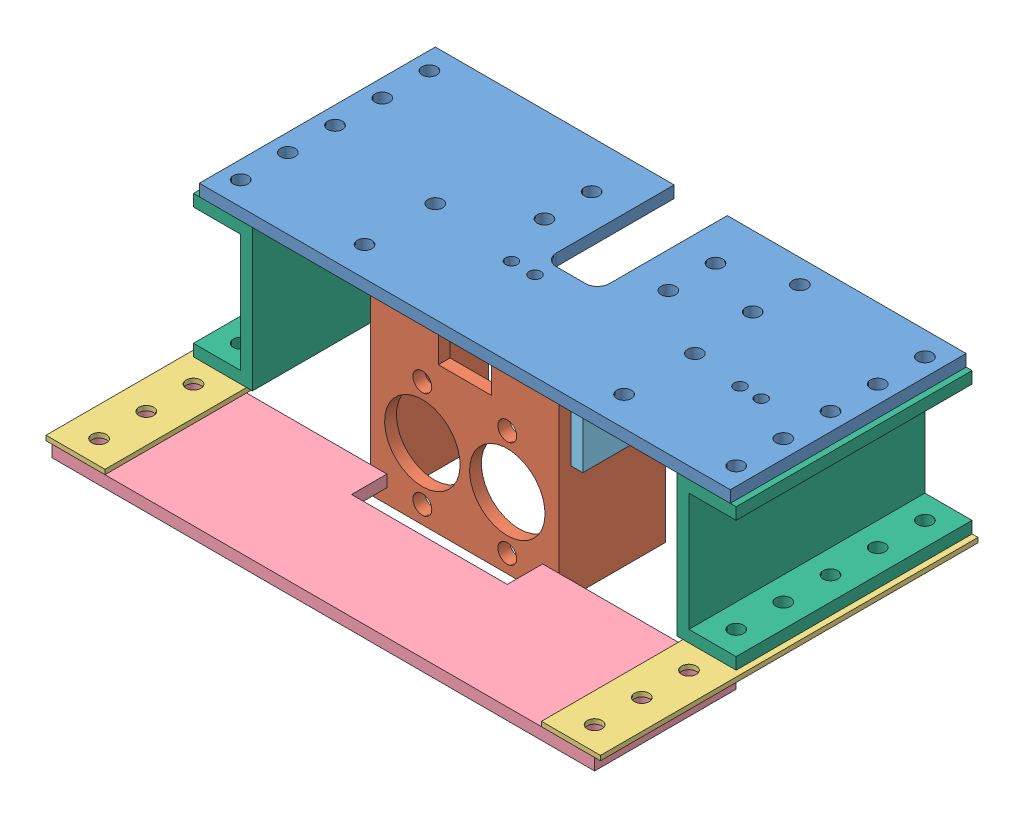
SolidWorks assembly Static Structure, configuration Default. Lengths in mm.
Overall size (298.45 99.21 203.2).
8 component instances, 6 part files, 23 mates.
Components (placement in the parent):
- Base Plate-1: Base Plate [Default] at (-589.1939 -24.2998 134.4277) x (-1 0 0) z (0 0 -1) size (285.75 6.35 127)
- C Bracket-1: C Bracket [Default] at (118.646 23.994 204.1743) x (1 0 0) z (0 -1 0) size (101.6 57.15 92.86)
- Chassis Tabs-1: Chassis Tabs [Default] at (40.6574 -52.206 309.9275) size (298.45 2.54 203.2)
- Foot Rest-1: Foot Rest [Default] at (-89.2227 -61.096 337.6277) size (292.1 6.35 76.2)
- L Bracket-1: L Bracket [Default] at (6.0273 23.994 255.0777) x (0 0 -1) z (-1 0 0) size (57.15 31.75 31.75)
- L Bracket-2: L Bracket [Default] at (107.6273 23.994 197.9277) x (0 0 1) z (1 0 0) size (57.15 31.75 31.75)
- Risers-1: Risers [Default] at (-86.4131 -13.4586 261.4277) x (0 0 -1) z (-1 0 0) size (127 76.2 31.75)
- Risers-2: Risers [Default] at (200.0678 -13.4586 134.4277) x (0 0 1) z (1 0 0) size (127 76.2 31.75)
Mates (geometry in assembly coordinates):
- Coincident1: coincident anti-aligned: plane of Base Plate-1 through (-589.1939 23.994 261.4277) normal (0 -1 0); plane of Risers-1 through (-86.4131 23.994 134.4277) normal (0 1 0)
- Coincident2: coincident anti-aligned: plane of Base Plate-1 through (-589.1939 23.994 261.4277) normal (0 -1 0); plane of Risers-2 through (200.0678 23.994 261.4277) normal (0 1 0)
- Coincident5: coincident anti-aligned: plane of Foot Rest-1 through (-89.2227 -54.746 337.6277) normal (0 1 0); plane of Chassis Tabs-1 through (40.6574 -54.746 309.9275) normal (0 -1 0)
- Coincident7: coincident aligned: plane of Chassis Tabs-1 through (-92.3977 -54.746 337.6277) normal (0 0 1); plane of Foot Rest-1 through (-89.2227 -54.746 337.6277) normal (0 0 1)
- Coincident8: coincident anti-aligned: plane of Chassis Tabs-1 through (40.6574 -52.206 309.9275) normal (0 1 0); plane of Risers-1 through (-86.4131 -52.206 134.4277) normal (0 -1 0)
- Coincident11: coincident anti-aligned: plane of C Bracket-1 through (6.0273 -68.8709 204.1743) normal (-1 0 0); plane of L Bracket-1 through (6.0273 23.994 197.9277) normal (1 0 0)
- Concentric9: concentric aligned: cylinder of C Bracket-1 through (107.6273 4.944 216.9777) axis (-1 0 0) radius 3.9688; cylinder of L Bracket-1 through (6.0283 4.944 216.9777) axis (-1 0 0) radius 3.9688
- Concentric10: concentric aligned: cylinder of C Bracket-1 through (107.6273 4.944 236.0277) axis (-1 0 0) radius 3.9688; cylinder of L Bracket-1 through (6.0283 4.944 236.0277) axis (-1 0 0) radius 3.9688
- Concentric11: concentric anti-aligned: cylinder of C Bracket-1 through (107.6273 4.944 236.0277) axis (-1 0 0) radius 3.9688; cylinder of L Bracket-2 through (107.6263 4.944 236.0277) axis (1 0 0) radius 3.9688
- Concentric12: concentric anti-aligned: cylinder of C Bracket-1 through (107.6273 4.944 216.9777) axis (-1 0 0) radius 3.9688; cylinder of L Bracket-2 through (107.6263 4.944 216.9777) axis (1 0 0) radius 3.9688
- Coincident13: coincident anti-aligned: plane of C Bracket-1 through (107.6273 -68.8709 204.1743) normal (1 0 0); plane of L Bracket-2 through (107.6273 23.994 255.0777) normal (-1 0 0)
- Coincident14: coincident anti-aligned: plane of Base Plate-1 through (-589.1939 23.994 261.4277) normal (0 -1 0); plane of L Bracket-1 through (6.0273 23.994 197.9277) normal (0 1 0)
- Concentric14: concentric anti-aligned: cylinder of Base Plate-1 through (190.1773 23.993 147.1277) axis (0 1 0) radius 3.9688; cylinder of Risers-2 through (190.1773 23.994 147.1277) axis (0 -1 0) radius 3.9688
- Concentric15: concentric anti-aligned: cylinder of Base Plate-1 through (190.1773 23.993 248.7277) axis (0 1 0) radius 3.9688; cylinder of Risers-2 through (190.1773 23.994 248.7277) axis (0 -1 0) radius 3.9688
- Concentric16: concentric anti-aligned: cylinder of Base Plate-1 through (-76.5227 23.993 147.1277) axis (0 1 0) radius 3.9688; cylinder of Risers-1 through (-76.5227 23.994 147.1277) axis (0 -1 0) radius 3.9688
- Concentric17: concentric anti-aligned: cylinder of Base Plate-1 through (-76.5227 23.993 248.7277) axis (0 1 0) radius 3.9688; cylinder of Risers-1 through (-76.5227 23.994 248.7277) axis (0 -1 0) radius 3.9688
- Coincident15: coincident aligned: plane of Chassis Tabs-1 through (-92.3977 -54.746 134.4277) normal (0 0 -1); plane of Risers-1 through (-86.4131 -13.4586 134.4277) normal (0 0 -1)
- Distance1: distance = 3.175 mm aligned: plane of Chassis Tabs-1 through (-92.3977 -54.746 134.4277) normal (-1 0 0); plane of Risers-1 through (-89.2227 -13.4586 134.4277) normal (-1 0 0)
- Distance2: distance = 3.175 mm aligned: plane of Foot Rest-1 through (-89.2227 -54.746 337.6277) normal (-1 0 0); plane of Chassis Tabs-1 through (-92.3977 -54.746 134.4277) normal (-1 0 0)
- Parallel1: parallel anti-aligned: line of Base Plate-1 through (-86.0477 30.344 261.4277) axis (0 0 -1); line of L Bracket-1 through (-25.7227 23.994 197.9277) axis (0 0 1)
- Concentric18: concentric anti-aligned: cylinder of Base Plate-1 through (-13.0227 23.993 207.4527) axis (0 1 0) radius 3.9688; cylinder of L Bracket-1 through (-13.0227 23.995 207.4527) axis (0 -1 0) radius 3.9688
- Concentric19: concentric anti-aligned: cylinder of Base Plate-1 through (-13.0227 23.993 245.5527) axis (0 1 0) radius 3.9688; cylinder of L Bracket-1 through (-13.0227 23.995 245.5527) axis (0 -1 0) radius 3.9688
- Concentric20: concentric anti-aligned: cylinder of Base Plate-1 through (126.6773 23.993 207.4527) axis (0 1 0) radius 3.9688; cylinder of L Bracket-2 through (126.6773 23.995 207.4527) axis (0 -1 0) radius 3.9688
